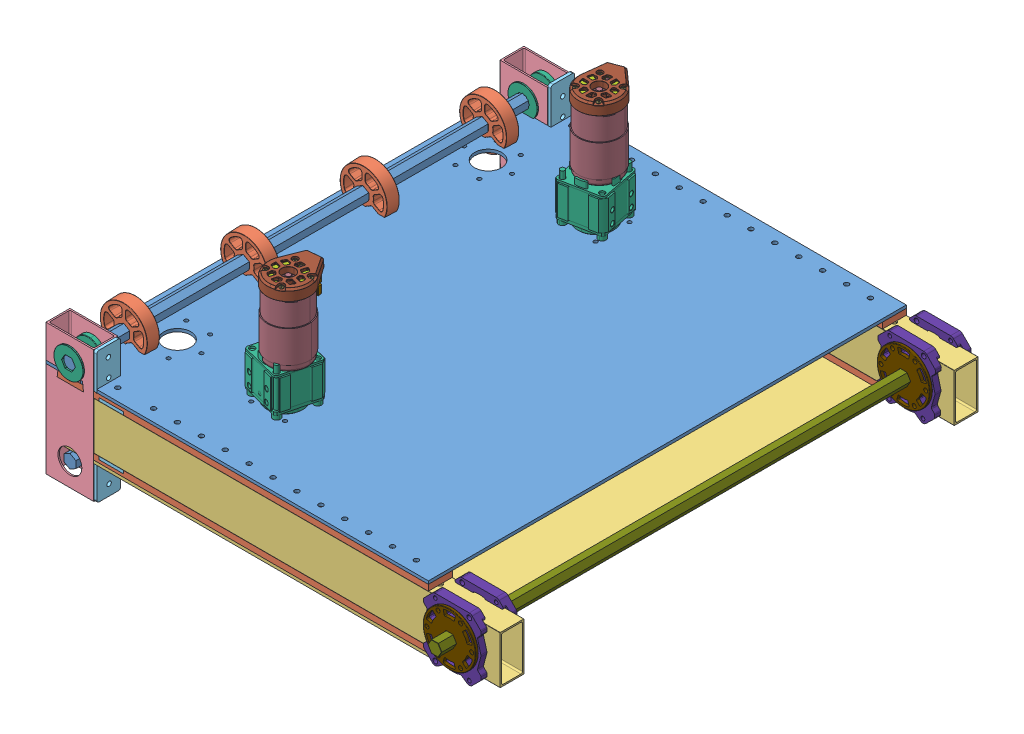
SolidWorks assembly t-piece top down new shooter assembly, configuration Default. Lengths in mm.
Overall size (503.63 249.41 558.8).
83 component instances, 24 part files, 104 mates.
Components (placement in the parent):
- ShooterPlate5-1: ShooterPlate5 [Default] at (-92.3523 325.8959 643.1212) size (406.4 3.17 508)
- ThickStick-3: ThickStick [Default] at (-92.3523 262.3959 643.1212) size (406.4 6.35 25.4)
- ThickStick-1: ThickStick [Default] at (-92.3523 319.5459 643.1212) size (406.4 6.35 25.4)
- ThickStick-2: ThickStick [Default] at (-92.3523 262.3959 160.5212) size (406.4 6.35 25.4)
- ThickStick-4: ThickStick [Default] at (-92.3523 319.5459 160.5212) size (406.4 6.35 25.4)
- ShooterPlate4-1: ShooterPlate4 [Default] at (-257.4523 259.2209 643.1212) size (406.4 3.17 508)
- 4in hex stealth wheel-2: 4in hex stealth wheel [Default] at (72.733 290.5093 554.2466) x (0 -1 0) z (-0.5 0 0.866025) size (25.4 101.6 101.6)
  - 4in Wheel Intergreated Hub 500 HEX.STEP-1: 4in Wheel Intergreated Hub 500 HEX.STEP [Default] at origin size (25.4 92.71 92.71)
  - 4in Tread.STEP-1: 4in Tread.STEP [Default] at origin size (25.4 101.6 101.6)
- 4in hex stealth wheel-3: 4in hex stealth wheel [Default] at (72.7256 290.5093 224.0405) x (0 -1 0) z (0.194202 0 0.980962) size (25.4 101.6 101.6)
  - 4in Wheel Intergreated Hub 500 HEX.STEP-1: 4in Wheel Intergreated Hub 500 HEX.STEP [Default] at origin size (25.4 92.71 92.71)
  - 4in Tread.STEP-1: 4in Tread.STEP [Default] at origin size (25.4 101.6 101.6)
- 4-1 Banebots-1: 4-1 Banebots [Default] at (72.7475 371.6159 224.0202) x (-0.194202 0 -0.980962) z (0 -1 0) size (47.62 47.62 76.19)
- 4-1 Banebots-2: 4-1 Banebots [Default] at (72.7467 371.6159 554.2209) x (-0.969356 0 -0.245662) z (0 -1 0) size (47.62 47.62 76.19)
- 775pro.step-1: 775pro.step [Default] at (71.7936 373.6479 219.2017) x (-0.934395 0 0.356239) z (0 -1 0) size (44.99 55.15 90.45)
  - 217-6457-000 Rev2.step-1: 217-6457-000 Rev2.step [Default] at (0 0 -66.1) x (1 0 0) z (0 1 0) size (44.99 33.26 55.15)
    - 217-6457-900 Rev1.step-1: 217-6457-900 Rev1.step [Default] at (0 5.3622 0) x (-1 0 0.000693) z (0.000693 0 1) size (41.5 28.13 51.51)
      - 217-6457-901 Rev3_Instruction Config.step-1: 217-6457-901 Rev3_Instruction Config.step [Default] at origin size (41.5 2.36 51.5)
      - 30-45BBS Rev1_SHORTENED CONTACT.step-1: 30-45BBS Rev1_SHORTENED CONTACT.step [Default] at (3.95 14.4494 26.711) x (0 1 0) z (0 0 -1) size (26 3.6 2)
      - 30-45BBS Rev1_SHORTENED CONTACT.step-2: 30-45BBS Rev1_SHORTENED CONTACT.step [Default] at (-3.9748 14.4494 26.711) x (0 1 0) z (0 0 -1) size (26 3.6 2)
      - PA45XX-X Rev1.step-1: PA45XX-X Rev1.step [Default] at (-8.4198 2.3622 73.1531) x (0 1 0) z (-1 0 0) size (24.71 8.41 8.41)
      - PA45XX-X Rev1.step-2: PA45XX-X Rev1.step [Default] at (-0.495 2.3622 73.1531) x (0 1 0) z (-1 0 0) size (24.71 8.41 8.41)
    - 217-6457-001 Rev4.step-1: 217-6457-001 Rev4.step [Default] at origin size (41.49 7.8 41.49)
    - 217-6457-002 Rev7.step-1: 217-6457-002 Rev7.step [Default] at (0 0.05 0) size (44.99 11.5 55.15)
    - 217-9191-008 Rev1.step-1: 217-9191-008 Rev1.step [Default] at (81.4247 7.8 32.3804) x (-0.560945 0 -0.827853) z (0 1 0) size (4.2 4.2 11.81)
    - 217-9191-008 Rev1.step-2: 217-9191-008 Rev1.step [Default] at (32.3804 7.8 -81.4247) x (-0.827853 0 0.560945) z (0 1 0) size (4.2 4.2 11.81)
    - 217-9191-008 Rev1.step-3: 217-9191-008 Rev1.step [Default] at (-81.4247 7.8 -32.3804) x (0.560945 0 0.827853) z (0 1 0) size (4.2 4.2 11.81)
    - 217-9191-008 Rev1.step-4: 217-9191-008 Rev1.step [Default] at (-32.3804 7.8 81.4247) x (0.827853 0 -0.560945) z (0 1 0) size (4.2 4.2 11.81)
  - 217-4347-000 Rev2.step-1: 217-4347-000 Rev2.step [Default] x (0 0 -1) z (-1 0 0) size (88 44.3 44.3)
- 775pro.step-2: 775pro.step [Default] at (77.5101 373.6479 555.4281) x (-0.994351 0 0.106139) z (0 -1 0) size (44.99 55.15 90.45)
  - 217-6457-000 Rev2.step-1: 217-6457-000 Rev2.step [Default] at (0 0 -66.1) x (1 0 0) z (0 1 0) size (44.99 33.26 55.15)
    - 217-6457-900 Rev1.step-1: 217-6457-900 Rev1.step [Default] at (0 5.3622 0) x (-1 0 0.000693) z (0.000693 0 1) size (41.5 28.13 51.51)
      - 217-6457-901 Rev3_Instruction Config.step-1: 217-6457-901 Rev3_Instruction Config.step [Default] at origin size (41.5 2.36 51.5)
      - 30-45BBS Rev1_SHORTENED CONTACT.step-1: 30-45BBS Rev1_SHORTENED CONTACT.step [Default] at (3.95 14.4494 26.711) x (0 1 0) z (0 0 -1) size (26 3.6 2)
      - 30-45BBS Rev1_SHORTENED CONTACT.step-2: 30-45BBS Rev1_SHORTENED CONTACT.step [Default] at (-3.9748 14.4494 26.711) x (0 1 0) z (0 0 -1) size (26 3.6 2)
      - PA45XX-X Rev1.step-1: PA45XX-X Rev1.step [Default] at (-8.4198 2.3622 73.1531) x (0 1 0) z (-1 0 0) size (24.71 8.41 8.41)
      - PA45XX-X Rev1.step-2: PA45XX-X Rev1.step [Default] at (-0.495 2.3622 73.1531) x (0 1 0) z (-1 0 0) size (24.71 8.41 8.41)
    - 217-6457-001 Rev4.step-1: 217-6457-001 Rev4.step [Default] at origin size (41.49 7.8 41.49)
    - 217-6457-002 Rev7.step-1: 217-6457-002 Rev7.step [Default] at (0 0.05 0) size (44.99 11.5 55.15)
    - 217-9191-008 Rev1.step-1: 217-9191-008 Rev1.step [Default] at (81.4247 7.8 32.3804) x (-0.560945 0 -0.827853) z (0 1 0) size (4.2 4.2 11.81)
    - 217-9191-008 Rev1.step-2: 217-9191-008 Rev1.step [Default] at (32.3804 7.8 -81.4247) x (-0.827853 0 0.560945) z (0 1 0) size (4.2 4.2 11.81)
    - 217-9191-008 Rev1.step-3: 217-9191-008 Rev1.step [Default] at (-81.4247 7.8 -32.3804) x (0.560945 0 0.827853) z (0 1 0) size (4.2 4.2 11.81)
    - 217-9191-008 Rev1.step-4: 217-9191-008 Rev1.step [Default] at (-32.3804 7.8 81.4247) x (0.827853 0 -0.560945) z (0 1 0) size (4.2 4.2 11.81)
  - 217-4347-000 Rev2.step-1: 217-4347-000 Rev2.step [Default] x (0 0 -1) z (-1 0 0) size (88 44.3 44.3)
- 4in hex shaft-1: 4in hex shaft [Default] at (72.7477 330.8489 224.0212) x (0.752436 0 -0.658665) z (0 -1 0) size (14.66 12.7 101.6)
- 4in hex shaft-2: 4in hex shaft [Default] at (72.7477 330.8489 554.2212) x (-0.969356 0 -0.245662) z (0 -1 0) size (14.66 12.7 101.6)
- am-2986 FR8ZZ Hex Bearing.step-1: am-2986 FR8ZZ Hex Bearing.step [Default] at (72.7477 255.9925 554.2212) x (0.969356 0 0.245662) z (0 1 0) size (31.12 31.12 7.93)
- am-2986 FR8ZZ Hex Bearing.step-2: am-2986 FR8ZZ Hex Bearing.step [Default] at (72.7477 322.6675 554.2212) x (1 0 0) z (0 1 0) size (31.12 31.12 7.93)
- am-2986 FR8ZZ Hex Bearing.step-3: am-2986 FR8ZZ Hex Bearing.step [Default] at (72.7477 322.6675 224.0212) x (0.194202 0 0.980962) z (0 1 0) size (31.12 31.12 7.93)
- am-2986 FR8ZZ Hex Bearing.step-4: am-2986 FR8ZZ Hex Bearing.step [Default] at (72.7477 255.9925 224.0212) x (0.946639 0 0.322297) z (0 1 0) size (31.12 31.12 7.93)
- shooteraxle-1: shooteraxle [Default] at (346.1982 295.6826 109.7212) x (0.5 0.866025 0) z (0 0 1) size (14.66 12.7 558.8)
- VersaBlock V2 (217-6111).step-1: VersaBlock V2 (217-6111).step [Default] at (346.1762 295.6699 131.9462) x (1 0 0) z (0 0 -1) size (61.04 66.67 9.53)
- VersaBlock V2 (217-6111).step-2: VersaBlock V2 (217-6111).step [Default] at (345.7977 295.9239 614.5462) x (1 0 0) z (0 0 -1) size (61.04 66.67 9.53)
- VersaBlock V2 (217-6111).step-3: VersaBlock V2 (217-6111).step [Default] at (345.7977 295.9239 646.2962) x (-1 0 0) z (0 0 1) size (61.04 66.67 9.53)
- VersaBlock V2 (217-6111).step-4: VersaBlock V2 (217-6111).step [Default] at (345.7977 295.9239 163.6962) x (-0.999903 0.013897 0) z (0 0 1) size (61.04 66.67 9.53)
- 1_2” Hex Bore Aluminum VersaHub (217-2592).step-1: 1_2” Hex Bore Aluminum VersaHub (217-2592).step [Default] at (346.1762 295.6699 138.2962) x (0 0 -1) z (0.866025 -0.5 0) size (12.7 55.88 55.88)
- 1_2” Hex Bore Aluminum VersaHub (217-2592).step-2: 1_2” Hex Bore Aluminum VersaHub (217-2592).step [Default] at (345.7977 295.9239 157.3462) x (0 0 1) z (-0.87289 -0.487916 0) size (12.7 55.88 55.88)
- 1_2” Hex Bore Aluminum VersaHub (217-2592).step-3: 1_2” Hex Bore Aluminum VersaHub (217-2592).step [Default] at (345.7977 295.9239 620.8962) x (0 0 -1) z (0.866025 0.5 0) size (12.7 55.88 55.88)
- 1_2” Hex Bore Aluminum VersaHub (217-2592).step-4: 1_2” Hex Bore Aluminum VersaHub (217-2592).step [Default] at (345.7977 295.9239 639.9462) x (0 0 1) z (-0.866025 0.5 0) size (12.7 55.88 55.88)
- axel and wheels for top down new Shooter design-1: axel and wheels for top down new Shooter design [Default] at (-188.6266 -12.7789 0) x (0.866025 -0.5 0) z (0 0 1) size (69.37 69.37 508)
  - .5in hex shaft 20in v2-1: .5in hex shaft 20in v2 [Default] at (-70.8055 365.9874 135.1212) size (14.66 12.7 508)
  - 2in complient wheel-1: 2in complient wheel [Default] at (-70.2556 366.9399 192.2712) x (0.5 -0.866025 0) z (0 0 1) size (50.78 50.78 12.7)
  - 2in complient wheel-2: 2in complient wheel [Default] at (-70.2556 366.9399 446.2712) size (50.78 50.78 12.7)
  - 2in complient wheel-3: 2in complient wheel [Default] at (-71.3555 366.9399 573.2712) size (50.78 50.78 12.7)
  - 2in complient wheel-4: 2in complient wheel [Default] at (-70.2556 366.9399 319.2712) size (50.78 50.78 12.7)
- axel and wheels for top down new Shooter design-2: axel and wheels for top down new Shooter design [Default] at (-188.6266 -103.6436 0) x (0.866025 -0.5 0) z (0 0 1) size (69.37 69.37 508)
  - .5in hex shaft 20in v2-1: .5in hex shaft 20in v2 [Default] at (-70.8055 365.9874 135.1212) size (14.66 12.7 508)
  - 2in complient wheel-1: 2in complient wheel [Default] at (-70.2556 366.9399 192.2712) x (0.5 -0.866025 0) z (0 0 1) size (50.78 50.78 12.7)
  - 2in complient wheel-2: 2in complient wheel [Default] at (-70.2556 366.9399 446.2712) size (50.78 50.78 12.7)
  - 2in complient wheel-3: 2in complient wheel [Default] at (-71.3555 366.9399 573.2712) size (50.78 50.78 12.7)
  - 2in complient wheel-4: 2in complient wheel [Default] at (-70.2556 366.9399 319.2712) size (50.78 50.78 12.7)
- side short v3-1: side short v3 [Default] at (364.8477 294.1459 630.4212) x (0 0 1) z (-1 0 0) size (25.4 50.8 431.8)
- side short v3-2: side short v3 [Default] at (364.8477 294.1459 147.8212) x (0 0 1) z (-1 0 0) size (25.4 50.8 431.8)
- 2x1 5.5in-1: 2x1 5.5in [Default] at (-66.9523 363.9959 147.8212) x (0 0 -1) z (0 -1 0) size (25.4 50.8 139.7)
- 2x1 5.5in-2: 2x1 5.5in [Default] at (-66.9523 363.9959 630.4212) x (0 0 -1) z (0 -1 0) size (25.4 50.8 139.7)
- 90 degree bracket-1: 90 degree bracket [Default] at (-19.3273 268.7459 147.8212) x (0 0 1) z (0 -1 0) size (25.4 44.45 47.62)
- 90 degree bracket-2: 90 degree bracket [Default] at (-41.5523 246.5209 630.4212) x (0 0 -1) z (1 0 0) size (25.4 44.45 47.62)
- 90 degree bracket-3: 90 degree bracket [Default] at (-41.5523 341.7709 630.4212) x (0 0 1) z (1 0 0) size (25.4 44.45 47.62)
- 90 degree bracket-4: 90 degree bracket [Default] at (-19.3273 319.5459 147.8212) x (0 0 -1) z (0 1 0) size (25.4 44.45 47.62)
- half in hex bearing for clibmer-1: half in hex bearing for clibmer [Default] at (-66.9523 339.5783 141.5245) x (0.997599 0.069261 0) z (0 0 -1) size (31.12 31.12 7.93)
- half in hex bearing for clibmer-2: half in hex bearing for clibmer [Default] at (-66.9523 339.5783 154.1178) size (31.12 31.12 7.93)
- half in hex bearing for clibmer-3: half in hex bearing for clibmer [Default] at (-66.9523 339.5783 636.7178) size (31.12 31.12 7.93)
- half in hex bearing for clibmer-4: half in hex bearing for clibmer [Default] at (-66.9523 339.5783 624.1245) x (-0.161121 -0.986935 0) z (0 0 -1) size (31.12 31.12 7.93)
Mates (geometry in assembly coordinates):
- Coincident4: coincident anti-aligned: plane of ShooterPlate5-1 through (-92.3523 325.8959 643.1212) normal (0 -1 0); plane of ThickStick-1 through (-92.3523 325.8959 643.1212) normal (0 1 0)
- Coincident5: coincident aligned: plane of ShooterPlate5-1 through (314.0477 329.0709 643.1212) normal (1 0 0); plane of ThickStick-1 through (314.0477 325.8959 643.1212) normal (1 0 0)
- Coincident6: coincident aligned: plane of ShooterPlate5-1 through (-92.3523 329.0709 643.1212) normal (0 0 1); plane of ThickStick-1 through (-92.3523 325.8959 643.1212) normal (0 0 1)
- Coincident11: coincident aligned: plane of ThickStick-1 through (-92.3523 325.8959 643.1212) normal (-1 0 0); plane of ThickStick-3 through (-92.3523 268.7459 643.1212) normal (-1 0 0)
- Coincident12: coincident anti-aligned: plane of ThickStick-3 through (-92.3523 262.3959 643.1212) normal (0 -1 0); plane of ShooterPlate4-1 through (-257.4523 262.3959 643.1212) normal (0 1 0)
- Coincident13: coincident aligned: plane of ShooterPlate5-1 through (-92.3523 329.0709 643.1212) normal (0 0 1); plane of ShooterPlate4-1 through (-257.4523 262.3959 643.1212) normal (0 0 1)
- Coincident14: coincident aligned: plane of ThickStick-3 through (314.0477 268.7459 643.1212) normal (1 0 0); plane of ShooterPlate4-1 through (314.0477 262.3959 643.1212) normal (1 0 0)
- Coincident15: coincident anti-aligned: plane of ShooterPlate5-1 through (-92.3523 325.8959 643.1212) normal (0 -1 0); plane of ThickStick-4 through (-92.3523 325.8959 160.5212) normal (0 1 0)
- Coincident16: coincident aligned: plane of ShooterPlate5-1 through (-92.3523 329.0709 643.1212) normal (-1 0 0); plane of ThickStick-4 through (-92.3523 325.8959 160.5212) normal (-1 0 0)
- Coincident18: coincident aligned: plane of ShooterPlate5-1 through (-92.3523 329.0709 135.1212) normal (0 0 -1); plane of ThickStick-4 through (-92.3523 325.8959 135.1212) normal (0 0 -1)
- Coincident21: coincident anti-aligned: plane of ThickStick-2 through (-92.3523 262.3959 160.5212) normal (0 -1 0); plane of ShooterPlate4-1 through (-257.4523 262.3959 643.1212) normal (0 1 0)
- Coincident23: coincident aligned: plane of ShooterPlate5-1 through (-92.3523 329.0709 643.1212) normal (-1 0 0); plane of ThickStick-2 through (-92.3523 268.7459 160.5212) normal (-1 0 0)
- Concentric10: concentric anti-aligned: cylinder of ShooterPlate5-1 through (72.7477 325.8959 224.0212) axis (0 1 0) radius 14.2875; cylinder of am-2986 FR8ZZ Hex Bearing.step-3 through (72.7477 330.5949 224.0212) axis (0 -1 0) radius 14.2875
- Coincident39: coincident anti-aligned: plane of ShooterPlate5-1 through (-92.3523 329.0709 643.1212) normal (0 1 0); plane of am-2986 FR8ZZ Hex Bearing.step-3 through (75.4607 329.0709 237.7252) normal (0 -1 0)
- Concentric11: concentric anti-aligned: cylinder of ShooterPlate5-1 through (72.7477 325.8959 554.2212) axis (0 1 0) radius 14.2875; cylinder of am-2986 FR8ZZ Hex Bearing.step-2 through (72.7477 330.5949 554.2212) axis (0 -1 0) radius 14.2875
- Coincident40: coincident anti-aligned: plane of ShooterPlate5-1 through (-92.3523 329.0709 643.1212) normal (0 1 0); plane of am-2986 FR8ZZ Hex Bearing.step-2 through (86.7177 329.0709 554.2212) normal (0 -1 0)
- Concentric12: concentric anti-aligned: cylinder of ShooterPlate4-1 through (72.7477 259.2209 554.2212) axis (0 1 0) radius 14.2875; cylinder of am-2986 FR8ZZ Hex Bearing.step-1 through (72.7477 263.9199 554.2212) axis (0 -1 0) radius 14.2875
- Coincident41: coincident anti-aligned: plane of ShooterPlate4-1 through (-257.4523 262.3959 643.1212) normal (0 1 0); plane of am-2986 FR8ZZ Hex Bearing.step-1 through (86.2896 262.3959 557.6531) normal (0 -1 0)
- Concentric13: concentric anti-aligned: cylinder of ShooterPlate4-1 through (72.7477 259.2209 224.0212) axis (0 1 0) radius 14.2875; cylinder of am-2986 FR8ZZ Hex Bearing.step-4 through (72.7477 263.9199 224.0212) axis (0 -1 0) radius 14.2875
- Coincident42: coincident anti-aligned: plane of ShooterPlate4-1 through (-257.4523 262.3959 643.1212) normal (0 1 0); plane of am-2986 FR8ZZ Hex Bearing.step-4 through (85.9723 262.3959 228.5236) normal (0 -1 0)
- Coincident44: coincident anti-aligned: plane of 4-1 Banebots-1 through (67.2306 330.8559 228.8507) normal (-0.980962 0 0.194202); plane of am-2986 FR8ZZ Hex Bearing.step-3 through (67.2306 330.5949 228.8507) normal (0.980962 0 -0.194202)
- Coincident53: coincident anti-aligned: plane of 4in hex shaft-2 through (67.6339 229.2489 559.4759) normal (-0.245662 0 0.969356); plane of am-2986 FR8ZZ Hex Bearing.step-1 through (74.7416 263.9199 561.2772) normal (0.245662 0 -0.969356)
- Coincident54: coincident anti-aligned: plane of 4in hex shaft-2 through (65.6401 229.2489 552.4199) normal (-0.962318 0 0.271928); plane of am-2986 FR8ZZ Hex Bearing.step-1 through (67.6339 263.9199 559.4759) normal (0.962318 0 -0.271928)
- Tangent9: tangent: plane of assembly; face of 4-1 Banebots-2; plane of 4in hex shaft-2 through (72.7477 330.8489 554.2212) normal (0 1 0)
- Coincident55: coincident aligned: plane of 4-1 Banebots-2 through (65.6401 330.8559 552.4199) normal (-0.716656 0 -0.697427); plane of 4in hex shaft-2 through (70.7538 229.2489 547.1651) normal (-0.716656 0 -0.697427)
- Coincident56: coincident aligned: plane of 4-1 Banebots-2 through (70.7538 330.8559 547.1651) normal (0.245662 0 -0.969356); plane of 4in hex shaft-2 through (77.8615 229.2489 548.9664) normal (0.245662 0 -0.969356)
- Tangent10: tangent: plane of assembly; face of 4-1 Banebots-2; plane of am-2986 FR8ZZ Hex Bearing.step-2 through (88.3052 330.5949 554.2212) normal (0 1 0)
- Tangent11: tangent: plane of assembly; face of 4-1 Banebots-1; plane of 4in hex shaft-1 through (72.7477 330.8489 224.0212) normal (0 1 0)
- Coincident57: coincident aligned: plane of 4-1 Banebots-1 through (65.8066 330.8559 221.658) normal (-0.658665 0 -0.752436); plane of 4in hex shaft-1 through (71.3238 229.2489 216.8284) normal (-0.658665 0 -0.752436)
- Coincident58: coincident aligned: plane of 4-1 Banebots-1 through (67.2306 330.8559 228.8507) normal (-0.980962 0 0.194202); plane of 4in hex shaft-1 through (65.8066 229.2489 221.658) normal (-0.980962 0 0.194202)
- Tangent12: tangent: plane of assembly; face of 4-1 Banebots-1; plane of am-2986 FR8ZZ Hex Bearing.step-3 through (75.769 330.5949 239.2825) normal (0 1 0)
- Coincident60: coincident anti-aligned: plane of 4in hex shaft-1 through (79.6888 229.2489 226.3843) normal (0.980962 0 -0.194202); plane of am-2986 FR8ZZ Hex Bearing.step-4 through (78.2648 263.9199 219.1916) normal (-0.980962 0 0.194202)
- Coincident61: coincident anti-aligned: plane of 4in hex shaft-1 through (74.1717 229.2489 231.2139) normal (0.658665 0 0.752436); plane of am-2986 FR8ZZ Hex Bearing.step-4 through (79.6888 263.9199 226.3843) normal (-0.658665 0 -0.752436)
- Coincident62: coincident anti-aligned: plane of 4in hex stealth wheel-3/4in Wheel Intergreated Hub 500 HEX.STEP-1 through (71.296 304.4334 216.819) normal (-0.322297 0 0.946639); plane of 4in hex shaft-1 through (78.2648 229.2489 219.1916) normal (0.322297 0 -0.946639)
- Coincident63: coincident anti-aligned: plane of 4in hex stealth wheel-3/4in Wheel Intergreated Hub 500 HEX.STEP-1 through (78.2648 304.4334 219.1916) normal (-0.980962 0 0.194202); plane of 4in hex shaft-1 through (79.6888 229.2489 226.3843) normal (0.980962 0 -0.194202)
- Concentric24: concentric anti-aligned: cylinder of VersaBlock V2 (217-6111).step-2 through (363.8845 323.2813 620.8962) axis (0 0 1) radius 2.0193; cylinder of VersaBlock V2 (217-6111).step-3 through (363.8845 323.2813 639.9462) axis (0 0 -1) radius 2.4892
- Coincident80: coincident anti-aligned: plane of VersaBlock V2 (217-6111).step-3 through (357.704 316.5461 649.4712) normal (0 0 1); plane of 1_2” Hex Bore Aluminum VersaHub (217-2592).step-4 through (352.9452 308.3036 649.4712) normal (0 0 -1)
- Concentric30: concentric aligned: cylinder of VersaBlock V2 (217-6111).step-3 through (333.8915 316.5461 649.4712) axis (0 0 1) radius 1.7272; cylinder of 1_2” Hex Bore Aluminum VersaHub (217-2592).step-4 through (333.8915 316.5461 566.8528) axis (0 0 1) radius 2.15
- Concentric31: concentric aligned: cylinder of VersaBlock V2 (217-6111).step-3 through (357.704 316.5461 649.4712) axis (0 0 1) radius 1.7272; cylinder of 1_2” Hex Bore Aluminum VersaHub (217-2592).step-4 through (357.704 316.5461 566.8528) axis (0 0 1) radius 2.15
- Coincident82: coincident anti-aligned: plane of VersaBlock V2 (217-6111).step-1 through (334.2699 316.2921 128.7712) normal (0 0 -1); plane of 1_2” Hex Bore Aluminum VersaHub (217-2592).step-1 through (353.3236 308.0496 128.7712) normal (0 0 1)
- Concentric32: concentric aligned: cylinder of VersaBlock V2 (217-6111).step-1 through (334.2699 316.2921 128.7712) axis (0 0 -1) radius 1.7272; cylinder of 1_2” Hex Bore Aluminum VersaHub (217-2592).step-1 through (334.2699 316.2921 211.3895) axis (0 0 -1) radius 2.15
- Concentric33: concentric aligned: cylinder of VersaBlock V2 (217-6111).step-1 through (358.0824 316.2921 128.7712) axis (0 0 -1) radius 1.7272; cylinder of 1_2” Hex Bore Aluminum VersaHub (217-2592).step-1 through (358.0824 316.2921 211.3895) axis (0 0 -1) radius 2.15
- Coincident83: coincident anti-aligned: plane of VersaBlock V2 (217-6111).step-4 through (357.9894 316.3786 166.8712) normal (0 0 1); plane of 1_2” Hex Bore Aluminum VersaHub (217-2592).step-2 through (338.823 308.4017 166.8712) normal (0 0 -1)
- Concentric35: concentric aligned: cylinder of VersaBlock V2 (217-6111).step-4 through (357.9894 316.3786 166.8712) axis (0 0 1) radius 1.7272; cylinder of 1_2” Hex Bore Aluminum VersaHub (217-2592).step-2 through (357.9894 316.3786 84.2528) axis (0 0 1) radius 2.15
- Concentric36: concentric aligned: cylinder of VersaBlock V2 (217-6111).step-4 through (334.1792 316.7096 166.8712) axis (0 0 1) radius 1.7272; cylinder of 1_2” Hex Bore Aluminum VersaHub (217-2592).step-2 through (334.1792 316.7096 84.2528) axis (0 0 1) radius 2.15
- Coincident84: coincident anti-aligned: plane of VersaBlock V2 (217-6111).step-2 through (333.8915 316.5461 611.3712) normal (0 0 -1); plane of 1_2” Hex Bore Aluminum VersaHub (217-2592).step-3 through (338.6502 308.3036 611.3712) normal (0 0 1)
- Concentric37: concentric aligned: cylinder of VersaBlock V2 (217-6111).step-2 through (357.704 316.5461 611.3712) axis (0 0 -1) radius 1.7272; cylinder of 1_2” Hex Bore Aluminum VersaHub (217-2592).step-3 through (357.704 316.5461 693.9895) axis (0 0 -1) radius 2.15
- Concentric38: concentric aligned: cylinder of VersaBlock V2 (217-6111).step-2 through (333.8915 316.5461 611.3712) axis (0 0 -1) radius 1.7272; cylinder of 1_2” Hex Bore Aluminum VersaHub (217-2592).step-3 through (333.8915 316.5461 693.9895) axis (0 0 -1) radius 2.15
- Distance6: distance = 76.2 mm: line of axel and wheels for top down new Shooter design-1/.5in hex shaft 20in v2-1 through (-66.9523 332.2459 643.1212) axis (0 0 -1); line of axel and wheels for top down new Shooter design-2/.5in hex shaft 20in v2-1 through (-66.9523 256.0459 643.1212) axis (0 0 -1)
- Coincident95: coincident aligned: plane of axel and wheels for top down new Shooter design-1/.5in hex shaft 20in v2-1 through (-73.3023 343.2444 643.1212) normal (-1 0 0); plane of axel and wheels for top down new Shooter design-2/.5in hex shaft 20in v2-1 through (-73.3023 252.3797 643.1212) normal (-1 0 0)
- Coincident96: coincident anti-aligned: plane of ThickStick-1 through (-92.3523 319.5459 643.1212) normal (0 -1 0); plane of side short v3-1 through (390.2477 319.5459 617.9752) normal (0 1 0)
- Coincident97: coincident anti-aligned: plane of ThickStick-3 through (-92.3523 268.7459 643.1212) normal (0 1 0); plane of side short v3-1 through (390.2477 268.7459 642.8672) normal (0 -1 0)
- Coincident98: coincident anti-aligned: plane of VersaBlock V2 (217-6111).step-2 through (345.7977 295.9239 617.7212) normal (0 0 1); plane of side short v3-1 through (390.2477 268.9999 617.7212) normal (0 0 -1)
- Concentric39: concentric aligned: cylinder of VersaBlock V2 (217-6111).step-3 through (345.7977 295.9239 644.7087) axis (0 0 -1) radius 15.9766; cylinder of side short v3-1 through (345.7977 295.9239 643.1212) axis (0 0 -1) radius 12.7
- Coincident102: coincident aligned: plane of ThickStick-3 through (-92.3523 268.7459 643.1212) normal (0 0 1); plane of side short v3-1 through (390.2477 319.2919 643.1212) normal (0 0 1)
- Coincident103: coincident aligned: plane of ShooterPlate4-1 through (-257.4523 262.3959 643.1212) normal (0 0 1); plane of side short v3-1 through (390.2477 319.2919 643.1212) normal (0 0 1)
- Coincident105: coincident anti-aligned: plane of ThickStick-2 through (-92.3523 268.7459 160.5212) normal (0 1 0); plane of side short v3-2 through (390.2477 268.7459 160.2672) normal (0 -1 0)
- Coincident106: coincident aligned: plane of ThickStick-4 through (-92.3523 325.8959 135.1212) normal (0 0 -1); plane of side short v3-2 through (390.2477 268.9999 135.1212) normal (0 0 -1)
- Coincident107: coincident aligned: plane of ShooterPlate5-1 through (-92.3523 329.0709 135.1212) normal (0 0 -1); plane of side short v3-2 through (390.2477 268.9999 135.1212) normal (0 0 -1)
- Coincident108: coincident anti-aligned: plane of VersaBlock V2 (217-6111).step-1 through (376.6943 319.5459 55.6292) normal (0 -1 0); plane of side short v3-2 through (390.2477 319.5459 135.3752) normal (0 1 0)
- Concentric42: concentric aligned: cylinder of VersaBlock V2 (217-6111).step-4 through (345.7977 295.9239 162.1087) axis (0 0 -1) radius 15.9766; cylinder of side short v3-2 through (345.7977 295.9239 160.5212) axis (0 0 -1) radius 12.7
- Parallel9: parallel aligned: plane of shooteraxle-1 through (342.532 302.0326 668.5212) normal (0 1 0); plane of side short v3-2 through (390.2477 319.5459 135.3752) normal (0 1 0)
- Distance8: distance = 25.4 mm aligned: plane of shooteraxle-1 through (346.1982 295.6826 668.5212) normal (0 0 1); plane of side short v3-1 through (390.2477 319.2919 643.1212) normal (0 0 1)
- Distance9: distance = 50.8 mm aligned: plane of ThickStick-1 through (-92.3523 325.8959 643.1212) normal (-1 0 0); plane of side short v3-1 through (-41.5523 319.2919 642.8672) normal (-1 0 0)
- Distance10: distance = 50.8 mm aligned: plane of ThickStick-4 through (-92.3523 325.8959 160.5212) normal (-1 0 0); plane of side short v3-2 through (-41.5523 319.2919 160.2672) normal (-1 0 0)
- Parallel12: parallel anti-aligned: plane of VersaBlock V2 (217-6111).step-3 through (315.2796 268.8729 722.6131) normal (0 1 0); plane of side short v3-1 through (390.2477 268.7459 642.8672) normal (0 -1 0)
- Concentric47: concentric aligned: cylinder of VersaBlock V2 (217-6111).step-3 through (345.7977 295.9239 644.7087) axis (0 0 -1) radius 15.9766; cylinder of side short v3-1 through (345.7977 295.9239 643.1212) axis (0 0 -1) radius 12.7
- Coincident117: coincident anti-aligned: plane of VersaBlock V2 (217-6111).step-3 through (345.7977 295.9239 643.1212) normal (0 0 -1); plane of side short v3-1 through (390.2477 319.2919 643.1212) normal (0 0 1)
- Coincident118: coincident anti-aligned: plane of shooteraxle-1 through (342.532 302.0326 668.5212) normal (0 1 0); plane of 1_2” Hex Bore Aluminum VersaHub (217-2592).step-1 through (342.5027 302.0326 138.2962) normal (0 -1 0)
- Concentric56: concentric anti-aligned: cylinder of VersaBlock V2 (217-6111).step-1 through (364.263 323.0273 138.2962) axis (0 0 1) radius 2.0193; cylinder of VersaBlock V2 (217-6111).step-4 through (364.263 323.0273 157.3462) axis (0 0 -1) radius 2.4892
- Coincident120: coincident anti-aligned: plane of VersaBlock V2 (217-6111).step-4 through (345.7977 295.9239 160.5212) normal (0 0 -1); plane of side short v3-2 through (390.2477 319.2919 160.5212) normal (0 0 1)
- Coincident121: coincident anti-aligned: plane of VersaBlock V2 (217-6111).step-1 through (346.1762 295.6699 135.1212) normal (0 0 1); plane of side short v3-2 through (390.2477 268.9999 135.1212) normal (0 0 -1)
- Parallel19: parallel anti-aligned: plane of VersaBlock V2 (217-6111).step-2 through (376.3158 319.7999 538.2292) normal (0 -1 0); plane of side short v3-1 through (390.2477 319.5459 617.9752) normal (0 1 0)
- Coincident124: coincident anti-aligned: plane of shooteraxle-1 through (353.5305 295.6826 668.5212) normal (0.866025 -0.5 0); plane of 1_2” Hex Bore Aluminum VersaHub (217-2592).step-1 through (353.5232 295.6699 138.2962) normal (-0.866025 0.5 0)
- Coincident125: coincident aligned: plane of axel and wheels for top down new Shooter design-2/.5in hex shaft 20in v2-1 through (-66.9523 248.7135 135.1212) normal (0 0 -1); plane of side short v3-2 through (390.2477 268.9999 135.1212) normal (0 0 -1)
- Coincident126: coincident aligned: plane of axel and wheels for top down new Shooter design-1/.5in hex shaft 20in v2-1 through (-66.9523 339.5782 135.1212) normal (0 0 -1); plane of side short v3-2 through (390.2477 268.9999 135.1212) normal (0 0 -1)
- Distance12: distance = 12.7 mm: line of axel and wheels for top down new Shooter design-1/.5in hex shaft 20in v2-1 through (-66.9523 332.2459 643.1212) axis (0 0 -1); plane of side short v3-2 through (390.2477 319.5459 135.3752) normal (0 1 0)
- Coincident129: coincident anti-aligned: plane of side short v3-2 through (-41.5523 319.2919 160.2672) normal (-1 0 0); plane of 2x1 5.5in-1 through (-41.5523 224.2959 160.2672) normal (1 0 0)
- Coincident130: coincident aligned: plane of side short v3-2 through (390.2477 268.9999 135.1212) normal (0 0 -1); plane of 2x1 5.5in-1 through (-41.8063 224.2959 135.1212) normal (0 0 -1)
- Distance13: distance = 44.45 mm aligned: plane of 2x1 5.5in-1 through (-41.8063 363.9959 135.3752) normal (0 1 0); plane of side short v3-2 through (390.2477 319.5459 135.3752) normal (0 1 0)
- Distance14: distance = 25.4 mm: line of axel and wheels for top down new Shooter design-2/.5in hex shaft 20in v2-1 through (-66.9523 256.0459 643.1212) axis (0 -1 0); plane of side short v3-1 through (-41.5523 319.2919 642.8672) normal (-1 0 0)
- Coincident133: coincident anti-aligned: plane of side short v3-1 through (-41.5523 319.2919 642.8672) normal (-1 0 0); plane of 2x1 5.5in-2 through (-41.5523 224.2959 642.8672) normal (1 0 0)
- Coincident134: coincident aligned: plane of side short v3-1 through (390.2477 319.2919 643.1212) normal (0 0 1); plane of 2x1 5.5in-2 through (-92.0983 224.2959 643.1212) normal (0 0 1)
- Distance15: distance = 44.45 mm aligned: plane of 2x1 5.5in-2 through (-41.8063 363.9959 617.9752) normal (0 1 0); plane of side short v3-1 through (390.2477 319.5459 617.9752) normal (0 1 0)
- Coincident138: coincident anti-aligned: plane of 2x1 5.5in-1 through (-41.5523 224.2959 160.2672) normal (1 0 0); plane of 90 degree bracket-4 through (-41.5523 367.1709 160.5212) normal (-1 0 0)
- Coincident139: coincident anti-aligned: plane of side short v3-2 through (390.2477 319.5459 135.3752) normal (0 1 0); plane of 90 degree bracket-4 through (-19.3273 319.5459 147.8212) normal (0 -1 0)
- Coincident140: coincident aligned: plane of side short v3-2 through (390.2477 268.9999 135.1212) normal (0 0 -1); plane of 90 degree bracket-4 through (2.8977 322.7209 135.1212) normal (0 0 -1)
- Coincident141: coincident anti-aligned: plane of side short v3-2 through (390.2477 268.7459 160.2672) normal (0 -1 0); plane of 90 degree bracket-1 through (-19.3273 268.7459 147.8212) normal (0 1 0)
- Coincident142: coincident anti-aligned: plane of 2x1 5.5in-1 through (-41.5523 224.2959 160.2672) normal (1 0 0); plane of 90 degree bracket-1 through (-41.5523 221.1209 135.1212) normal (-1 0 0)
- Coincident143: coincident aligned: plane of side short v3-2 through (390.2477 268.9999 135.1212) normal (0 0 -1); plane of 90 degree bracket-1 through (2.8977 265.5709 135.1212) normal (0 0 -1)
- Coincident144: coincident anti-aligned: plane of 2x1 5.5in-2 through (-41.5523 224.2959 642.8672) normal (1 0 0); plane of 90 degree bracket-3 through (-41.5523 341.7709 630.4212) normal (-1 0 0)
- Coincident145: coincident anti-aligned: plane of side short v3-1 through (390.2477 319.5459 617.9752) normal (0 1 0); plane of 90 degree bracket-3 through (6.0727 319.5459 617.7212) normal (0 -1 0)
- Coincident146: coincident aligned: plane of side short v3-1 through (390.2477 319.2919 643.1212) normal (0 0 1); plane of 90 degree bracket-3 through (6.0727 322.7209 643.1212) normal (0 0 1)
- Coincident147: coincident anti-aligned: plane of side short v3-1 through (390.2477 268.7459 642.8672) normal (0 -1 0); plane of 90 degree bracket-2 through (6.0727 268.7459 643.1212) normal (0 1 0)
- Coincident148: coincident anti-aligned: plane of 2x1 5.5in-2 through (-41.5523 224.2959 642.8672) normal (1 0 0); plane of 90 degree bracket-2 through (-41.5523 246.5209 630.4212) normal (-1 0 0)
- Coincident149: coincident aligned: plane of 2x1 5.5in-2 through (-92.0983 224.2959 643.1212) normal (0 0 1); plane of 90 degree bracket-2 through (-38.3773 224.2959 643.1212) normal (0 0 1)
- Coincident150: coincident: plane of 2x1 5.5in-1 through (-92.0983 224.2959 160.5212) normal (0 0 1); plane of half in hex bearing for clibmer-2 through (-52.9823 339.5783 160.5212) normal (0 0 -1)
- Concentric57: concentric aligned: cylinder of 2x1 5.5in-1 through (-66.9523 339.5783 160.5212) axis (0 0 -1) radius 12.7; cylinder of half in hex bearing for clibmer-2 through (-66.9523 339.5783 162.0452) axis (0 0 -1) radius 14.2875
- Coincident151: coincident: plane of 2x1 5.5in-1 through (-41.8063 224.2959 135.1212) normal (0 0 -1); plane of half in hex bearing for clibmer-1 through (-53.0158 340.5459 135.1212) normal (0 0 1)
- Concentric58: concentric anti-aligned: cylinder of 2x1 5.5in-1 through (-66.9523 339.5783 160.5212) axis (0 0 -1) radius 12.7; cylinder of half in hex bearing for clibmer-1 through (-66.9523 339.5783 133.5972) axis (0 0 1) radius 14.2875
- Coincident152: coincident: plane of 2x1 5.5in-2 through (-92.0983 224.2959 643.1212) normal (0 0 1); plane of half in hex bearing for clibmer-3 through (-52.9823 339.5783 643.1212) normal (0 0 -1)
- Concentric59: concentric aligned: cylinder of 2x1 5.5in-2 through (-66.9523 339.5783 643.1212) axis (0 0 -1) radius 12.7; cylinder of half in hex bearing for clibmer-3 through (-66.9523 339.5783 644.6452) axis (0 0 -1) radius 14.2875
- Coincident153: coincident: plane of 2x1 5.5in-2 through (-41.8063 224.2959 617.7212) normal (0 0 -1); plane of half in hex bearing for clibmer-4 through (-69.2032 325.7908 617.7212) normal (0 0 1)
- Concentric60: concentric anti-aligned: cylinder of 2x1 5.5in-2 through (-66.9523 339.5783 643.1212) axis (0 0 -1) radius 12.7; cylinder of half in hex bearing for clibmer-4 through (-66.9523 339.5783 616.1972) axis (0 0 1) radius 14.2875
